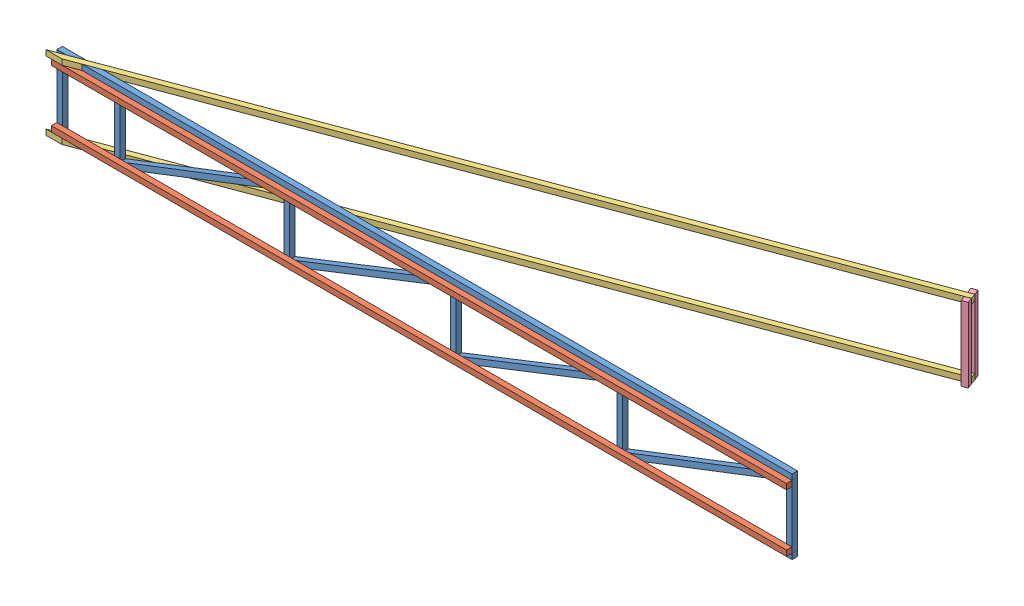
SolidWorks assembly boomAssembly, configuration Default. Lengths in mm.
Overall size (426.21 42.7 148.35).
6 component instances, 4 part files, 15 mates.
Components (placement in the parent):
- cross brace compression-3: cross brace compression [Default] at (-109.2004 207.2528 347.8228) size (423.18 42.7 3.17)
- Part1-1: Part1 [Default] at (-109.2004 207.2528 354.1728) size (423.18 36.35 3.17)
- tension members-3: tension members [Default] at (269.1249 227.7278 350.9978) x (-1 0 0) z (0 0 1) size (390.29 3.18 145.38)
- tension members-4: tension members [Default] at (269.1249 267.2528 350.9978) x (-1 0 0) z (0 0 1) size (390.29 3.18 145.38)
- jHookMount-1: jHookMount [Default] at (255.7958 215.9028 213.0827) x (0.936777 0 -0.349926) z (0 1 0) size (3.17 3.17 42.7)
- jHookMount-2: jHookMount [Default] at (258.0179 215.9028 219.0313) x (0.936777 0 -0.349926) z (0 1 0) size (3.17 3.17 42.7)
Mates (geometry in assembly coordinates):
- Coincident4: coincident: plane of cross brace compression-3 through (-127.3754 207.2528 350.9978) normal (-1 0 0); plane of Part1-1 through (-127.3754 207.2528 357.3478) normal (-1 0 0)
- Coincident5: coincident: plane of cross brace compression-3 through (-109.2004 207.2528 354.1728) normal (0 0 1); plane of Part1-1 through (-109.2004 207.2528 354.1728) normal (0 0 -1)
- Coincident7: coincident: plane of Part1-1 through (-109.2004 207.2528 357.3478) normal (0 0 1); plane of tension members-3 through (291.79 227.7278 357.3478) normal (0 0 1)
- Coincident8: coincident: plane of cross brace compression-3 through (-107.5644 219.0778 352.2026) normal (-0.349926 0 -0.936777); plane of tension members-3 through (223.3948 176.3778 228.5752) normal (0.349926 0 0.936777)
- Coincident9: coincident: plane of Part1-1 through (-109.2004 219.0778 357.3478) normal (0 -1 0); plane of tension members-3 through (291.79 219.0778 350.9978) normal (0 1 0)
- Coincident10: coincident: plane of cross brace compression-3 through (-108.6754 255.4278 349.2284) normal (0.349926 0 0.936777); plane of tension members-4 through (222.2837 215.9028 225.6009) normal (-0.349926 0 -0.936777)
- Coincident11: coincident: plane of Part1-1 through (-109.2004 207.2528 357.3478) normal (0 0 1); plane of tension members-4 through (291.79 267.2528 357.3478) normal (0 0 1)
- Coincident12: coincident: plane of cross brace compression-3 through (-131.8656 258.6028 347.8228) normal (0 1 0); plane of tension members-4 through (291.79 258.6028 350.9978) normal (0 1 0)
- Coincident13: coincident: plane of cross brace compression-3 through (-131.8656 219.0778 347.8228) normal (0 1 0); plane of Part1-1 through (-109.2004 219.0778 357.3478) normal (0 -1 0)
- Coincident14: coincident: plane of tension members-3 through (222.2837 176.3778 225.6009) normal (-0.349926 0 -0.936777); plane of jHookMount-1 through (255.7958 258.6028 213.0827) normal (0.349926 0 0.936777)
- Coincident15: coincident: plane of tension members-4 through (291.79 258.6028 350.9978) normal (0 1 0); plane of jHookMount-1 through (255.7958 258.6028 213.0827) normal (0 1 0)
- Coincident16: coincident: plane of tension members-3 through (305.6112 215.9028 337.3686) normal (0.936777 0 -0.349926); plane of jHookMount-1 through (258.7701 258.6028 211.9717) normal (0.936777 0 -0.349926)
- Coincident17: coincident: plane of tension members-3 through (223.3948 176.3778 228.5752) normal (0.349926 0 0.936777); plane of jHookMount-2 through (256.9068 258.6028 216.057) normal (-0.349926 0 -0.936777)
- Coincident18: coincident: plane of tension members-3 through (305.6112 215.9028 337.3686) normal (0.936777 0 -0.349926); plane of jHookMount-2 through (260.9921 258.6028 217.9203) normal (0.936777 0 -0.349926)
- Coincident19: coincident: plane of tension members-3 through (291.79 215.9028 350.9978) normal (0 -1 0); plane of jHookMount-2 through (258.0179 215.9028 219.0313) normal (0 -1 0)
